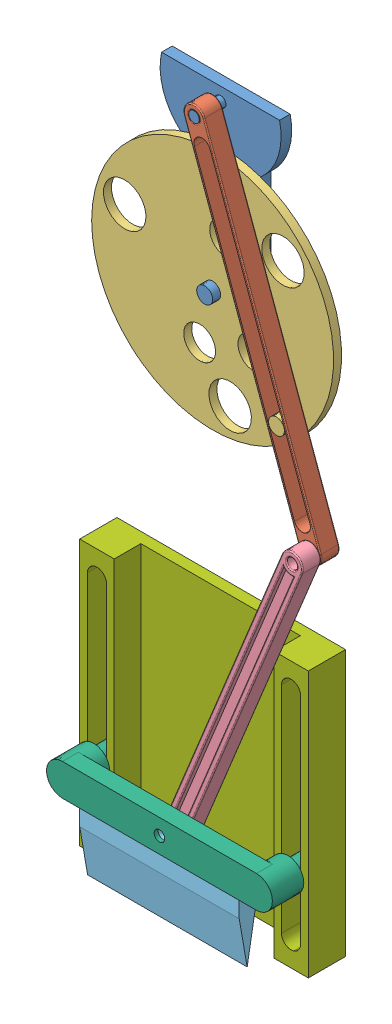
SolidWorks assembly Assem6, configuration Default. Lengths in mm.
Overall size (640.1 1320.63 135).
7 component instances, 7 part files, 19 mates.
Components (placement in the parent):
- stand_r-1: stand_r [Default] at origin size (227.5 360.52 70)
- Part_L2-1: Part_L2 [Default] at (109.4464 -300.7016 52.5) x (-0.34202 0.939693 0) z (0 0 1) size (680 40 35)
- Part_R-1: Part_R [Default] at (0 -300 27.5) x (-0.631138 -0.775671 0) z (0 0 1) size (455 455 50)
- Part_L3-1: Part_L3 [Default] at (109.4464 -869.9577 87.5) x (-0.377402 -0.92605 0) z (0 0 1) size (620 40 35)
- blade-1: blade [Default] at (150 -1168.5121 120) size (300 161 30)
- rabet-1: rabet [Default] at (0 -1138.5121 135) size (425 60 106)
- base-2: base [Default] at (0 -1045 0) size (430 500 70)
Mates (geometry in assembly coordinates):
- Concentric1: concentric anti-aligned: cylinder of stand_r-1 through (0 -300 50) axis (0 0 -1) radius 15; cylinder of Part_R-1 through (0 -300 -22.4264) axis (0 0 1) radius 15
- Coincident1: coincident anti-aligned: plane of stand_r-1 through (0 0 20) normal (0 0 1); plane of Part_R-1 through (0 -300 20) normal (0 0 -1)
- Slot2: slot aligned: plane of Part_L2-1 through (29.9561 -36.9849 75) normal (-0.939693 -0.34202 0); cylinder of Part_R-1 through (155.1341 -426.2276 112.4264) axis (0 0 -1) radius 15; cylinder of Part_L2-1 through (15.3909 -42.2862 75) axis (0 0 -1) radius 15.5
- Coincident2: coincident anti-aligned: plane of Part_L2-1 through (218.8929 -601.4033 35) normal (0 0 -1); plane of Part_R-1 through (0 -300 35) normal (0 0 1)
- Concentric3: concentric anti-aligned: cylinder of stand_r-1 through (0 0 98.2843) axis (0 0 -1) radius 10; cylinder of Part_L2-1 through (0 0 35) axis (0 0 1) radius 10
- Concentric4: concentric anti-aligned: cylinder of Part_L2-1 through (218.8929 -601.4033 35) axis (0 0 1) radius 10; cylinder of Part_L3-1 through (218.8929 -601.4033 105) axis (0 0 -1) radius 10
- Coincident3: coincident anti-aligned: plane of Part_L2-1 through (218.8929 -601.4033 70) normal (0 0 1); plane of Part_L3-1 through (218.8929 -601.4033 70) normal (0 0 -1)
- Concentric5: concentric anti-aligned: cylinder of blade-1 through (0 -1138.5121 127.5) axis (0 0 -1) radius 10; cylinder of rabet-1 through (0 -1138.5121 76.7157) axis (0 0 1) radius 10
- Coincident5: coincident anti-aligned: plane of blade-1 through (150 -1168.5121 127.5) normal (0 0 1); plane of rabet-1 through (-30 -1123.5121 127.5) normal (0 0 -1)
- Concentric6: concentric aligned: cylinder of Part_L3-1 through (0 -1138.5121 105) axis (0 0 -1) radius 10; cylinder of blade-1 through (0 -1138.5121 127.5) axis (0 0 -1) radius 10
- Coincident6: coincident anti-aligned: plane of blade-1 through (30 -1123.5121 127.5) normal (1 0 0); plane of rabet-1 through (30 -1123.5121 112.5) normal (-1 0 0)
- Coincident7: coincident anti-aligned: plane of Part_L3-1 through (218.8929 -601.4033 105) normal (0 0 1); plane of rabet-1 through (0 -1138.5121 105) normal (0 0 -1)
- Parallel3: parallel aligned: plane of base-2 through (0 -795 20) normal (0 1 0)
- Coincident12: coincident anti-aligned: plane of base-2 through (0 -1045 0) normal (0 0 -1)
- Coincident13: coincident aligned: plane of base-2 through (0 -1045 0) normal (1 0 0)
- Slot3: slot aligned: cylinder of rabet-1 through (-182.5 -1138.5121 29) axis (0 0 1) radius 18; plane of base-2 through (-164.5 -1045 23) normal (-1 0 0); cylinder of base-2 through (-182.5 -842.5 23) axis (0 0 1) radius 18
- Slot4: slot aligned: cylinder of rabet-1 through (182.5 -1138.5121 29) axis (0 0 1) radius 18; plane of base-2 through (164.5 -1045 23) normal (1 0 0); cylinder of base-2 through (182.5 -1247.5 23) axis (0 0 1) radius 18
- Distance2: distance = 820 mm aligned: plane of stand_r-1 through (0 25 20) normal (0 1 0); plane of base-2 through (0 -795 20) normal (0 1 0)
- Angle1: planar angle = 1.919862 rad aligned: line of stand_r-1 through (-110.9687 25 20) axis (1 0 0); line of Part_L2-1 through (235.8074 -595.2469 70) axis (-0.34202 0.939693 0)
